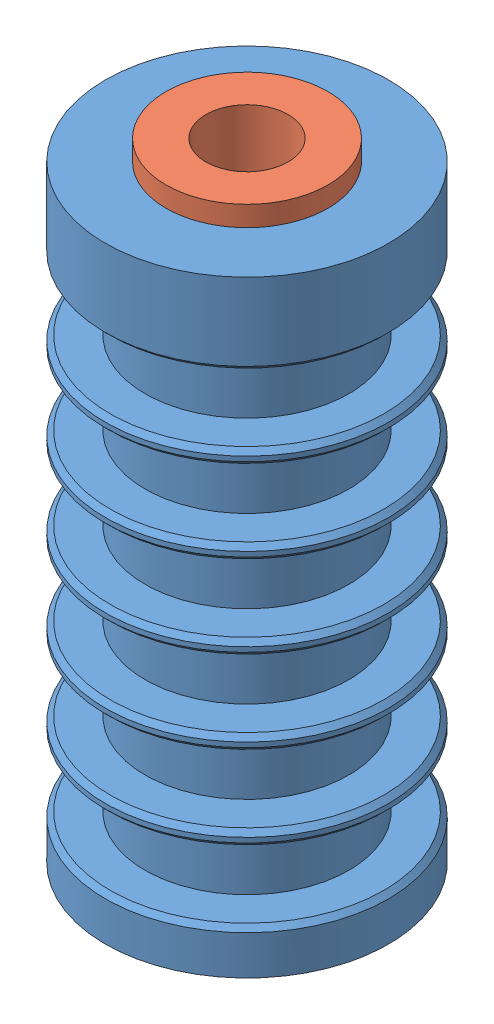
SolidWorks assembly WinchGuideRoller, configuration Roller 3. Lengths in mm.
Overall size (26.43 50.8 26.43).
3 component instances, 2 part files, 2 mates.
Components (placement in the parent):
- LargeStainlessRoller-1: LargeStainlessRoller [Roller 3] at (30.1625 29.7656 12.7) x (0.977234 0 0.212165) z (0 -1 0) size (22.23 22.23 47.62)
- 6362K213_WATER-RESISTANT DRY-RUNNING SLEEVE BRNG-1: 6362K213_WATER-RESISTANT DRY-RUNNING SLEEVE BRNG [6362K213] at (30.1625 56.7531 12.7) x (-0.837169 0 -0.546944) z (-0.546944 0 0.837169) size (12.7 9.53 12.7)
- 6362K213_WATER-RESISTANT DRY-RUNNING SLEEVE BRNG-2: 6362K213_WATER-RESISTANT DRY-RUNNING SLEEVE BRNG [6362K213] at (30.1625 5.9531 12.7) size (12.7 9.53 12.7)
Mates (geometry in assembly coordinates):
- Coincident19: coincident aligned: circle of LargeStainlessRoller-1; circle of 6362K213_WATER-RESISTANT DRY-RUNNING SLEEVE BRNG-1
- Coincident20: coincident anti-aligned: circle of LargeStainlessRoller-1; circle of 6362K213_WATER-RESISTANT DRY-RUNNING SLEEVE BRNG-2
